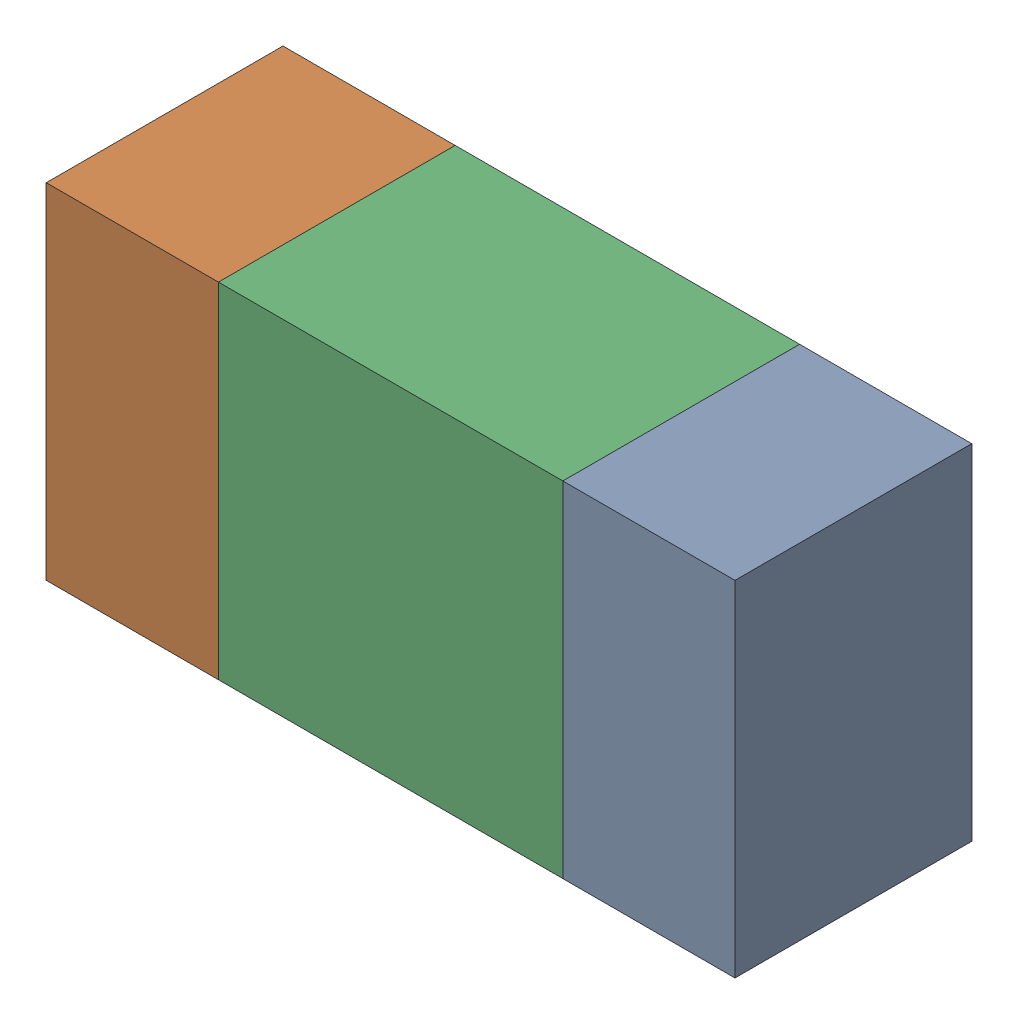
SolidWorks assembly R32, configuration ﾃﾞﾌｫﾙﾄ. Lengths in mm.
Overall size (1.6 0.8 0.55).
6 component instances, 2 part files, 0 mates.
Components (placement in the parent):
- 689261512-1: 689261512 [ﾃﾞﾌｫﾙﾄ] at (6.3149 13.6526 -1.7503) size (0.4 0.8 0.55)
  - Extruded_32-1: Extruded_32 [ﾃﾞﾌｫﾙﾄ] at origin size (0.4 0.8 0.55)
- 689261512-2: 689261512 [ﾃﾞﾌｫﾙﾄ] at (5.1149 13.6526 -1.7503) size (0.4 0.8 0.55)
  - Extruded_32-1: Extruded_32 [ﾃﾞﾌｫﾙﾄ] at origin size (0.4 0.8 0.55)
- 689261648-1: 689261648 [ﾃﾞﾌｫﾙﾄ] at (5.715 13.6526 -1.7503) size (0.8 0.8 0.55)
  - Extruded_33-1: Extruded_33 [ﾃﾞﾌｫﾙﾄ] at origin size (0.8 0.8 0.55)
